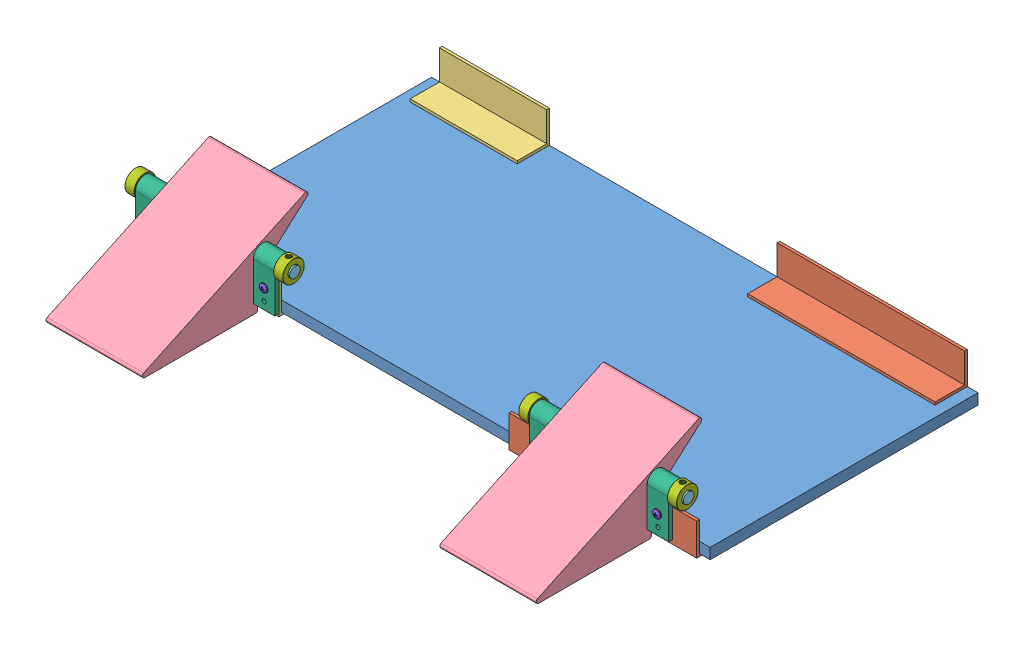
SolidWorks assembly Board_HingedWedge_Assembly, configuration Default. Lengths in mm.
Overall size (685.8 96.62 457.15).
29 component instances, 9 part files, 44 mates.
Components (placement in the parent):
- Board base-1: Board base [Default] at (-95.436 -14.789 849.8329) size (647.7 12.7 317.5)
- L-Bracket long-1: L-Bracket long [Default] at (140.2954 -2.5095 1012.6945) x (-1 0 0) z (0 0 -1) size (222.25 38.1 38.1)
- L-Bracket short-1: L-Bracket short [Default] at (-443.3458 35.2993 692.0195) size (127 38.1 38.1)
- L-Bracket short-2: L-Bracket short [Default] at (-320.0378 19.4243 1012.6945) x (-1 0 0) z (0 0 -1) size (127 38.1 38.1)
- L-Bracket long-2: L-Bracket long [Default] at (-8.3289 13.3655 692.0195) size (222.25 38.1 38.1)
- ComponentAssembly-1: ComponentAssembly [Default] at (207.8673 -80.6693 962.3423) x (0 0 1) z (-1 0 0) size (196.58 94.96 190.5)
  - HingedWedge3DPrint-1: HingedWedge3DPrint [Default] at (185.4507 56.0723 141.8841) x (0.999998 -0.002183 0) z (0 0 1) size (196.37 94.54 114.3)
  - Shaft-1: Shaft [Default] at (43.9387 113.5053 46.6341) x (0.780539 0.625107 0) z (0 0 1) size (12.7 12.7 190.5)
  - AluminumPlate-1: AluminumPlate [Default] at (44.0657 113.5053 224.4341) x (0 -1 0) z (0 0 -1) size (56.97 22.1 25.4)
  - AluminumPlate-2: AluminumPlate [Default] at (44.0657 113.5053 84.7341) x (0 -1 0) z (0 0 -1) size (56.97 22.1 25.4)
  - 9946K150_SET SCREW SHAFT COLLAR-1: 9946K150_SET SCREW SHAFT COLLAR [9946K15] at (43.9387 113.5053 229.9903) x (0.473025 0.881049 0) z (0 0 1) size (25.4 25.4 11.11)
  - 9946K150_SET SCREW SHAFT COLLAR-2: 9946K150_SET SCREW SHAFT COLLAR [9946K15] at (43.9387 113.5053 53.7778) size (25.4 25.4 11.11)
- ComponentAssembly-2: ComponentAssembly [Default] at (-258.8577 -82.3203 962.3423) x (0 0 1) z (-1 0 0) size (196.58 94.96 190.5)
  - HingedWedge3DPrint-1: HingedWedge3DPrint [Default] at (185.4507 56.0723 141.8841) x (0.999998 -0.002183 0) z (0 0 1) size (196.37 94.54 114.3)
  - Shaft-1: Shaft [Default] at (43.9387 113.5053 46.6341) x (0.780539 0.625107 0) z (0 0 1) size (12.7 12.7 190.5)
  - AluminumPlate-1: AluminumPlate [Default] at (44.0657 113.5053 224.4341) x (0 -1 0) z (0 0 -1) size (56.97 22.1 25.4)
  - AluminumPlate-2: AluminumPlate [Default] at (44.0657 113.5053 84.7341) x (0 -1 0) z (0 0 -1) size (56.97 22.1 25.4)
  - 9946K150_SET SCREW SHAFT COLLAR-1: 9946K150_SET SCREW SHAFT COLLAR [9946K15] at (43.9387 113.5053 229.9903) x (0.473025 0.881049 0) z (0 0 1) size (25.4 25.4 11.11)
  - 9946K150_SET SCREW SHAFT COLLAR-2: 9946K150_SET SCREW SHAFT COLLAR [9946K15] at (43.9387 113.5053 53.7778) size (25.4 25.4 11.11)
- 91772A242_18-8 SS PAN HEAD PHILLIPS MACHINE SCREW-1: 91772A242_18-8 SS PAN HEAD PHILLIPS MACHINE SCREW [91772A242] at (135.8332 9.7728 1004.757) size (9.47 9.47 16.54)
- 91831A011_TYPE 18-8 STAINLESS STL NYLON-INSERT LOCKNUT-1: 91831A011_TYPE 18-8 STAINLESS STL NYLON-INSERT LOCKNUT [91831A011] at (135.8332 9.7728 1009.5195) x (1 0 0) z (0 1 0) size (9.53 6.11 11)
- 91772A242_18-8 SS PAN HEAD PHILLIPS MACHINE SCREW-3: 91772A242_18-8 SS PAN HEAD PHILLIPS MACHINE SCREW [91772A242] at (-470.5918 8.1218 1004.1489) size (9.47 9.47 16.54)
- 91831A011_TYPE 18-8 STAINLESS STL NYLON-INSERT LOCKNUT-3: 91831A011_TYPE 18-8 STAINLESS STL NYLON-INSERT LOCKNUT [91831A011] at (-470.5918 8.1218 1009.5195) x (1 0 0) z (0 1 0) size (9.53 6.11 11)
- 91772A242_18-8 SS PAN HEAD PHILLIPS MACHINE SCREW-4: 91772A242_18-8 SS PAN HEAD PHILLIPS MACHINE SCREW [91772A242] at (-330.8918 8.1218 1004.1489) size (9.47 9.47 16.54)
- 91831A011_TYPE 18-8 STAINLESS STL NYLON-INSERT LOCKNUT-4: 91831A011_TYPE 18-8 STAINLESS STL NYLON-INSERT LOCKNUT [91831A011] at (-330.8918 8.1218 1009.5195) x (1 0 0) z (0 1 0) size (9.53 6.11 11)
- 91772A242_18-8 SS PAN HEAD PHILLIPS MACHINE SCREW-8: 91772A242_18-8 SS PAN HEAD PHILLIPS MACHINE SCREW [91772A242] at (-3.8668 9.7728 1004.757) size (9.47 9.47 16.54)
- 91831A011_TYPE 18-8 STAINLESS STL NYLON-INSERT LOCKNUT-8: 91831A011_TYPE 18-8 STAINLESS STL NYLON-INSERT LOCKNUT [91831A011] at (-3.8668 9.7728 1009.5195) x (1 0 0) z (0 1 0) size (9.53 6.11 11)
- 91772A242_18-8 SS PAN HEAD PHILLIPS MACHINE SCREW-9: 91772A242_18-8 SS PAN HEAD PHILLIPS MACHINE SCREW [91772A242] at (156.2691 -14.789 999.8564) x (1 0 0) z (0 1 0) size (9.47 9.47 16.54)
- 91831A011_TYPE 18-8 STAINLESS STL NYLON-INSERT LOCKNUT-9: 91831A011_TYPE 18-8 STAINLESS STL NYLON-INSERT LOCKNUT [91831A011] at (156.2691 -17.964 999.8564) x (1 0 0) z (0 0 -1) size (9.53 6.11 11)
Mates (geometry in assembly coordinates):
- Coincident1: coincident: plane of Board base-1 through (-95.436 -2.089 849.8329) normal (0 1 0); plane of L-Bracket long-2 through (-45.1418 -2.089 730.1195) normal (0 -1 0)
- Coincident3: coincident: plane of L-Bracket short-2 through (-318.1918 -14.789 1009.5195) normal (0 1 0); plane of Board base-1 through (-95.436 -14.789 849.8329) normal (0 -1 0)
- Coincident4: coincident: plane of Board base-1 through (-95.436 -2.089 849.8329) normal (0 1 0); plane of L-Bracket short-1 through (-445.1918 -2.089 730.1195) normal (0 -1 0)
- Parallel2: parallel: line of Board base-1 through (-457.8918 -2.089 692.0195) axis (0 0 1); line of L-Bracket long-2 through (177.1082 1.086 695.1945) axis (0 0 1)
- Coincident13: coincident: plane of L-Bracket long-1 through (177.1082 -14.789 1009.5195) normal (0 1 0); plane of Board base-1 through (-95.436 -14.789 849.8329) normal (0 -1 0)
- Parallel6: parallel: plane of Board base-1 through (-457.8918 -2.089 1009.5195) normal (0 0 1); plane of L-Bracket short-2 through (-320.0378 19.4243 1012.6945) normal (0 0 1)
- Parallel7: parallel: plane of L-Bracket short-1 through (-443.3458 35.2993 692.0195) normal (0 0 -1); plane of Board base-1 through (-457.8918 -2.089 692.0195) normal (0 0 -1)
- Coincident27: coincident: line of Board base-1 through (-457.8918 -2.089 1009.5195) axis (1 0 0); plane of L-Bracket short-2 through (-320.0378 19.4243 1009.5195) normal (0 0 -1)
- Coincident28: coincident: plane of L-Bracket long-1 through (177.1082 -14.789 1009.5195) normal (0 1 0); plane of Board base-1 through (-95.436 -14.789 849.8329) normal (0 -1 0)
- Distance11: distance = 12.7 mm: plane of L-Bracket short-2 through (-445.1918 20.136 974.5945) normal (-1 0 0); plane of Board base-1 through (-457.8918 -2.089 692.0195) normal (-1 0 0)
- Distance12: distance = 12.7 mm: plane of L-Bracket short-1 through (-445.1918 36.011 730.1195) normal (-1 0 0); plane of Board base-1 through (-457.8918 -2.089 692.0195) normal (-1 0 0)
- Distance14: distance = 12.7 mm: plane of L-Bracket long-1 through (177.1082 20.136 974.5945) normal (1 0 0); plane of Board base-1 through (189.8082 -2.089 692.0195) normal (1 0 0)
- Distance16: distance = 12.7 mm: plane of L-Bracket long-2 through (177.1082 36.011 730.1195) normal (1 0 0); plane of Board base-1 through (189.8082 -2.089 692.0195) normal (1 0 0)
- Coincident29: coincident: plane of L-Bracket long-1 through (140.2954 -2.5095 1012.6945) normal (0 0 1); plane of ComponentAssembly-1/AluminumPlate-2 through (148.5332 32.836 1012.6945) normal (0 0 -1)
- Coincident30: coincident: plane of L-Bracket long-1 through (140.2954 -2.5095 1012.6945) normal (0 0 1); plane of ComponentAssembly-1/AluminumPlate-1 through (8.8332 32.836 1012.6945) normal (0 0 -1)
- Tangent2: tangent: plane of L-Bracket long-1 through (177.1082 20.136 974.5945) normal (0 1 0); cylinder of ComponentAssembly-1/9946K150_SET SCREW SHAFT COLLAR-2 through (148.5332 32.836 1006.281) axis (1 0 0) radius 12.7
- Coincident35: coincident: plane of L-Bracket short-2 through (-320.0378 19.4243 1012.6945) normal (0 0 1); plane of ComponentAssembly-2/AluminumPlate-1 through (-457.8918 31.185 1012.6945) normal (0 0 -1)
- Coincident36: coincident: plane of L-Bracket short-2 through (-320.0378 19.4243 1012.6945) normal (0 0 1); plane of ComponentAssembly-2/AluminumPlate-2 through (-318.1918 31.185 1012.6945) normal (0 0 -1)
- Coincident37: coincident: plane of L-Bracket short-2 through (-318.1918 20.136 974.5945) normal (0 1 0); line of ComponentAssembly-2/AluminumPlate-1 through (-457.8918 20.136 1006.408) axis (-1 0 0)
- Coincident38: coincident: plane of L-Bracket short-2 through (-318.1918 20.136 974.5945) normal (0 1 0); line of ComponentAssembly-2/AluminumPlate-2 through (-318.1918 20.136 1006.408) axis (-1 0 0)
- Coincident39: coincident: plane of L-Bracket short-2 through (-318.1918 20.136 974.5945) normal (1 0 0); plane of ComponentAssembly-2/AluminumPlate-2 through (-318.1918 31.185 1006.408) normal (1 0 0)
- Concentric1: concentric: circle of ComponentAssembly-1/AluminumPlate-2; circle of 91772A242_18-8 SS PAN HEAD PHILLIPS MACHINE SCREW-1
- Coincident40: coincident: plane of ComponentAssembly-1/AluminumPlate-2 through (148.5332 32.836 1017.457) normal (0 0 1); circle of 91772A242_18-8 SS PAN HEAD PHILLIPS MACHINE SCREW-1
- Concentric2: concentric: circle of 91772A242_18-8 SS PAN HEAD PHILLIPS MACHINE SCREW-1; circle of 91831A011_TYPE 18-8 STAINLESS STL NYLON-INSERT LOCKNUT-1
- Coincident42: coincident: plane of L-Bracket long-1 through (140.2954 -2.5095 1009.5195) normal (0 0 -1); plane of 91831A011_TYPE 18-8 STAINLESS STL NYLON-INSERT LOCKNUT-1 through (131.0707 1.5239 1009.5195) normal (0 0 1)
- Concentric7: concentric: circle of ComponentAssembly-2/AluminumPlate-1; circle of 91772A242_18-8 SS PAN HEAD PHILLIPS MACHINE SCREW-3
- Coincident48: coincident: plane of ComponentAssembly-2/AluminumPlate-1 through (-457.8918 31.185 1017.457) normal (0 0 1); circle of 91772A242_18-8 SS PAN HEAD PHILLIPS MACHINE SCREW-3
- Concentric8: concentric: circle of 91772A242_18-8 SS PAN HEAD PHILLIPS MACHINE SCREW-3; circle of 91831A011_TYPE 18-8 STAINLESS STL NYLON-INSERT LOCKNUT-3
- Coincident49: coincident: plane of L-Bracket short-2 through (-320.0378 19.4243 1009.5195) normal (0 0 -1); plane of 91831A011_TYPE 18-8 STAINLESS STL NYLON-INSERT LOCKNUT-3 through (-475.3543 -0.1271 1009.5195) normal (0 0 1)
- Concentric9: concentric: circle of 91772A242_18-8 SS PAN HEAD PHILLIPS MACHINE SCREW-4; circle of 91831A011_TYPE 18-8 STAINLESS STL NYLON-INSERT LOCKNUT-4
- Concentric10: concentric: circle of ComponentAssembly-2/AluminumPlate-2; circle of 91831A011_TYPE 18-8 STAINLESS STL NYLON-INSERT LOCKNUT-4
- Coincident50: coincident: plane of ComponentAssembly-2/AluminumPlate-2 through (-318.1918 31.185 1017.457) normal (0 0 1); circle of 91772A242_18-8 SS PAN HEAD PHILLIPS MACHINE SCREW-4
- Coincident51: coincident: plane of L-Bracket short-2 through (-320.0378 19.4243 1009.5195) normal (0 0 -1); plane of 91831A011_TYPE 18-8 STAINLESS STL NYLON-INSERT LOCKNUT-4 through (-335.6543 -0.1271 1009.5195) normal (0 0 1)
- Coincident58: coincident: plane of L-Bracket long-1 through (140.2954 -2.5095 1009.5195) normal (0 0 -1); plane of 91831A011_TYPE 18-8 STAINLESS STL NYLON-INSERT LOCKNUT-8 through (-8.6293 1.5239 1009.5195) normal (0 0 1)
- Concentric17: concentric: circle of 91772A242_18-8 SS PAN HEAD PHILLIPS MACHINE SCREW-8; circle of 91831A011_TYPE 18-8 STAINLESS STL NYLON-INSERT LOCKNUT-8
- Concentric18: concentric: circle of ComponentAssembly-1/AluminumPlate-1; circle of 91831A011_TYPE 18-8 STAINLESS STL NYLON-INSERT LOCKNUT-8
- Coincident59: coincident: plane of ComponentAssembly-1/AluminumPlate-1 through (8.8332 32.836 1017.457) normal (0 0 1); circle of 91772A242_18-8 SS PAN HEAD PHILLIPS MACHINE SCREW-8
- Width1: width: plane of L-Bracket long-1 through (-45.1418 20.136 974.5945) normal (-1 0 0); plane of L-Bracket long-1 through (177.1082 20.136 974.5945) normal (1 0 0); plane of ComponentAssembly-1/Shaft-1 through (-29.2668 32.836 1006.281) normal (-1 0 0); plane of ComponentAssembly-1/Shaft-1 through (161.2332 32.836 1006.281) normal (1 0 0)
- Coincident60: coincident: plane of Board base-1 through (-457.8918 -2.089 1009.5195) normal (0 0 1); plane of L-Bracket long-1 through (140.2954 -2.5095 1009.5195) normal (0 0 -1)
- Coincident62: coincident: plane of Board base-1 through (-457.8918 -2.089 692.0195) normal (0 0 -1); plane of L-Bracket long-2 through (-8.3289 13.3655 692.0195) normal (0 0 -1)
- Coincident63: coincident: plane of Board base-1 through (-457.8918 -2.089 692.0195) normal (0 0 -1); plane of L-Bracket short-1 through (-443.3458 35.2993 692.0195) normal (0 0 -1)
- Coincident64: coincident: plane of Board base-1 through (-95.436 -2.089 849.8329) normal (0 1 0); plane of 91772A242_18-8 SS PAN HEAD PHILLIPS MACHINE SCREW-9 through (156.2691 -2.089 999.8564) normal (0 -1 0)
- Coincident65: coincident: plane of L-Bracket long-1 through (177.1082 -17.964 974.5945) normal (0 -1 0); plane of 91831A011_TYPE 18-8 STAINLESS STL NYLON-INSERT LOCKNUT-9 through (151.5066 -17.964 1008.1053) normal (0 1 0)
- Concentric22: concentric: circle of 91772A242_18-8 SS PAN HEAD PHILLIPS MACHINE SCREW-9; circle of 91831A011_TYPE 18-8 STAINLESS STL NYLON-INSERT LOCKNUT-9
